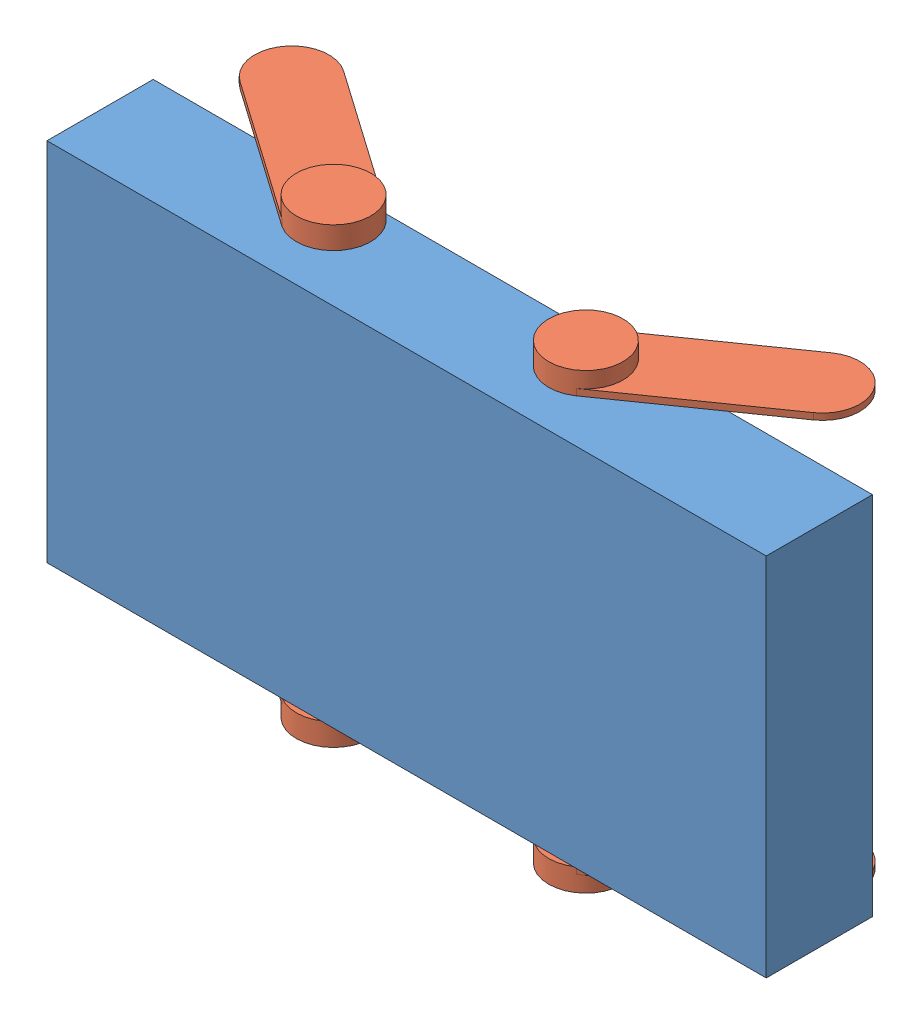
SolidWorks assembly summit_X, configuration Default. Lengths in mm.
Overall size (677 484 244.27).
5 component instances, 2 part files, 9 mates.
Components (placement in the parent):
- chassis-1: chassis [Default] at origin size (677 344 100)
- suspension_link-1: suspension_link [Default] at (118.75 192 0) x (0.34202 0 -0.939693) z (-0.939693 0 -0.34202) size (201.06 21 161.77)
- suspension_link-2: suspension_link [Default] at (-118.75 192 0) x (-1 0 0) z (0 0 1) size (201.06 21 161.77)
- suspension_link-3: suspension_link [Default] at (-118.75 -192 0) x (-0.34202 0 -0.939693) z (0.939693 0 -0.34202) size (201.06 21 161.77)
- suspension_link-4: suspension_link [Default] at (118.75 -192 0) size (201.06 21 161.77)
Mates (geometry in assembly coordinates):
- Coincident1: coordinate: point of chassis-1; point of assembly
- Distance4: distance = 20 mm anti-aligned: plane of suspension_link-1 through (118.75 192 0) normal (0 -1 0); plane of chassis-1 through (0 172 0) normal (0 1 0)
- Concentric3: concentric aligned: line of chassis-1 through (546.4345 118.75 272.0533) axis (0 0 -1); cylinder of suspension_link-1 through (118.75 198 0) axis (0 -1 0) radius 35
- Distance5: distance = 20 mm anti-aligned: plane of suspension_link-2 through (-118.75 192 0) normal (0 -1 0); plane of chassis-1 through (0 172 0) normal (0 1 0)
- Concentric4: concentric aligned: line of chassis-1 through (548.4617 -118.75 277.5009) axis (0 0 -1); cylinder of suspension_link-2 through (-118.75 198 0) axis (0 -1 0) radius 35
- Distance6: distance = 20 mm anti-aligned: plane of suspension_link-4 through (118.75 -192 0) normal (0 1 0); plane of chassis-1 through (0 -172 0) normal (0 -1 0)
- Concentric5: concentric anti-aligned: line of chassis-1 through (546.4345 118.75 272.0533) axis (0 0 -1); cylinder of suspension_link-4 through (118.75 -198 0) axis (0 1 0) radius 35
- Distance7: distance = 20 mm anti-aligned: plane of suspension_link-3 through (-118.75 -192 0) normal (0 1 0); plane of chassis-1 through (0 -172 0) normal (0 -1 0)
- Concentric6: concentric anti-aligned: line of chassis-1 through (548.4617 -118.75 277.5009) axis (0 0 -1); cylinder of suspension_link-3 through (-118.75 -198 0) axis (0 1 0) radius 35
